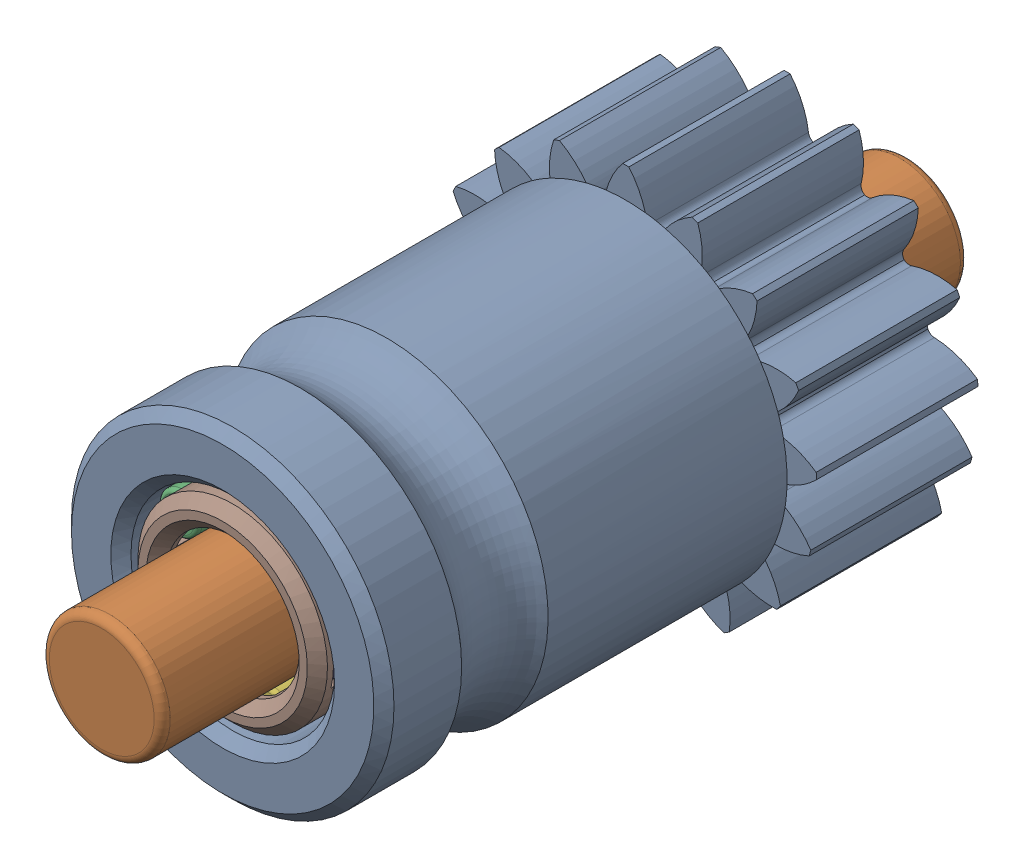
SolidWorks assembly Direct_Drivegear_without_setscrew (1), configuration Default. Lengths in mm.
Overall size (9.47 9.43 20).
16 component instances, 8 part files, 0 mates.
Components (placement in the parent):
- Direct_Drivegear_without_setscrew (1)-1: Direct_Drivegear_without_setscrew (1) [Default] at origin size (9.47 9.43 14)
- stift 3 x 20 (1)-1: stift 3 x 20 (1) [Default] at (0 0 -7) x (0.469401 0.882985 0) z (0.882985 -0.469401 0) size (3 20 3)
- K3x5x7 Needlebearing (1)-1: K3x5x7 Needlebearing (1) [Default] at (0 0 6.5) x (0.594234 0.804292 0) z (0 0 1) size (4.8 4.85 7)
  - K3x5x7 Needlebearing (1)_3-1: K3x5x7 Needlebearing (1)_3 [Default] at origin size (1 1 6)
  - K3x5x7 Needlebearing (1)_5-1: K3x5x7 Needlebearing (1)_5 [Default] at origin size (1 1 6)
  - K3x5x7 Needlebearing (1)-1: K3x5x7 Needlebearing (1) [Default] at origin size (1 1 6)
  - K3x5x7 Needlebearing (1)_4-1: K3x5x7 Needlebearing (1)_4 [Default] at origin size (1 1 6)
  - K3x5x7 Needlebearing (1)_2-1: K3x5x7 Needlebearing (1)_2 [Default] at origin size (1 1 6)
  - K3x5x7 Needlebearing (1)_6-1: K3x5x7 Needlebearing (1)_6 [Default] at origin size (4.7 4.7 7)
- K3x5x7 Needlebearing (1)-2: K3x5x7 Needlebearing (1) [Default] at (0 0 -0.501) x (0.563856 0.825873 0) z (0 0 1) size (4.8 4.85 7)
  - K3x5x7 Needlebearing (1)_3-1: K3x5x7 Needlebearing (1)_3 [Default] at origin size (1 1 6)
  - K3x5x7 Needlebearing (1)_5-1: K3x5x7 Needlebearing (1)_5 [Default] at origin size (1 1 6)
  - K3x5x7 Needlebearing (1)-1: K3x5x7 Needlebearing (1) [Default] at origin size (1 1 6)
  - K3x5x7 Needlebearing (1)_4-1: K3x5x7 Needlebearing (1)_4 [Default] at origin size (1 1 6)
  - K3x5x7 Needlebearing (1)_2-1: K3x5x7 Needlebearing (1)_2 [Default] at origin size (1 1 6)
  - K3x5x7 Needlebearing (1)_6-1: K3x5x7 Needlebearing (1)_6 [Default] at origin size (4.7 4.7 7)
